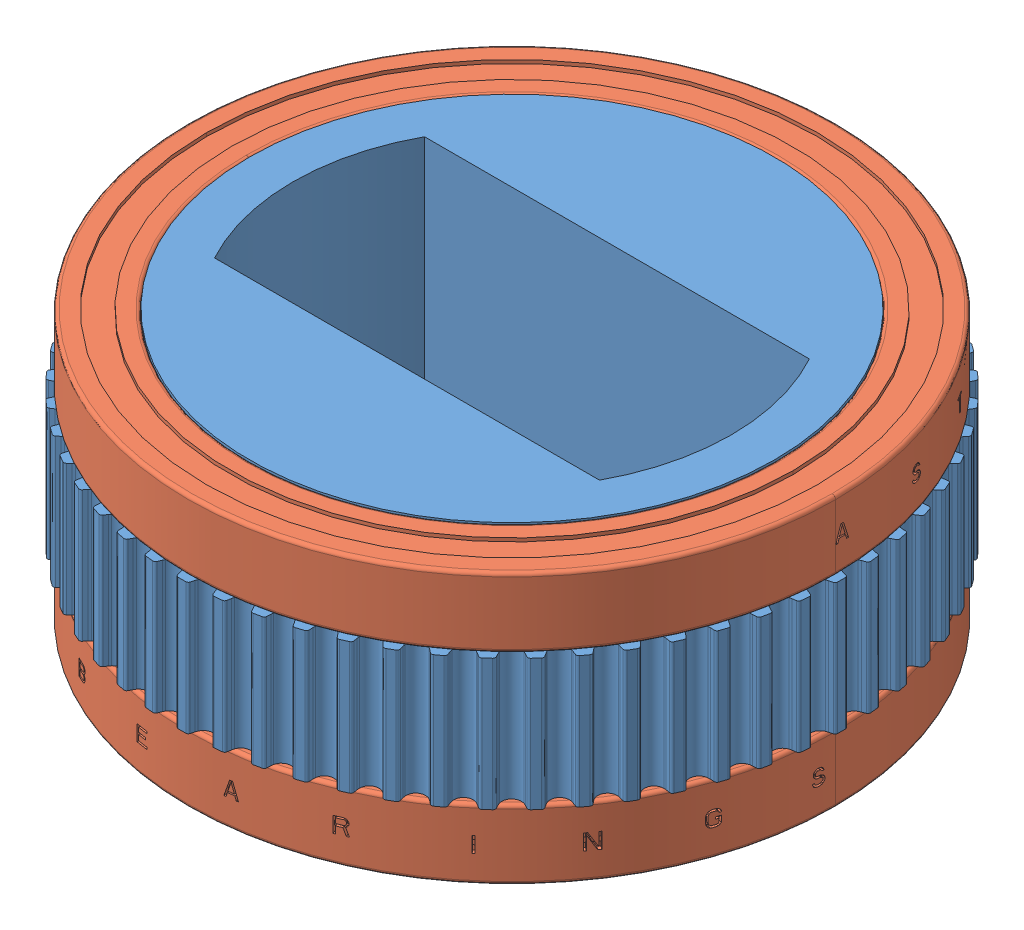
SolidWorks assembly Second_reduction_module, configuration Default. Lengths in mm.
Overall size (37.7 15.5 37.7).
5 component instances, 4 part files, 8 mates.
Components (placement in the parent):
- DRIVEN_PULLEY_SECOND_REDUCTION-1: DRIVEN_PULLEY_SECOND_REDUCTION [По умолчанию] at (8.5756 23.3079 32.9704) x (-1 0 0) z (0 -1 0) size (37.7 37.7 15.5)
- Bearings_6706-2RS.stp-1: Bearings_6706-2RS.stp [Default] at (8.5756 23.7518 32.9704) x (0 1 0) z (0 0 -1) size (3.99 37.01 37.01)
- Bearings_6706-2RS.stp-2: Bearings_6706-2RS.stp [Default] at (8.5756 12.264 32.9704) x (0 1 0) z (0 0 1) size (3.99 37.01 37.01)
- M3_INSERT.step-1: M3_INSERT.step [Default] at (8.5756 10.2579 42.9704) size (4.52 4 4.53)
- M3_INSERT.step-2: M3_INSERT.step [Default] at (8.5756 10.2579 22.9704) size (4.52 4 4.53)
Mates (geometry in assembly coordinates):
- Concentric1: concentric anti-aligned: cylinder of DRIVEN_PULLEY_SECOND_REDUCTION-1 through (8.5756 25.7579 32.9704) axis (0 -1 0) radius 15; cylinder of Bearings_6706-2RS.stp-1 through (8.5756 21.5585 32.9704) axis (0 1 0) radius 14.9987
- Coincident1: coincident anti-aligned: plane of DRIVEN_PULLEY_SECOND_REDUCTION-1 through (10.757 21.7579 14.3981) normal (0 1 0); plane of Bearings_6706-2RS.stp-1 through (8.5756 21.7579 32.9704) normal (0 -1 0)
- Coincident2: coincident anti-aligned: plane of DRIVEN_PULLEY_SECOND_REDUCTION-1 through (8.5756 14.2579 32.9704) normal (0 -1 0); plane of Bearings_6706-2RS.stp-2 through (8.5756 14.2579 32.9704) normal (0 1 0)
- Concentric2: concentric aligned: cylinder of DRIVEN_PULLEY_SECOND_REDUCTION-1 through (8.5756 10.2579 32.9704) axis (0 1 0) radius 15; cylinder of Bearings_6706-2RS.stp-2 through (8.5756 10.0707 32.9704) axis (0 1 0) radius 14.9987
- Concentric3: concentric aligned: cylinder of DRIVEN_PULLEY_SECOND_REDUCTION-1 through (8.5756 14.2579 22.9704) axis (0 -1 0) radius 2.25; cylinder of M3_INSERT.step-2 through (8.5756 10.2579 22.9704) axis (0 -1 0) radius 1.85
- Coincident3: coincident aligned: plane of DRIVEN_PULLEY_SECOND_REDUCTION-1 through (8.5756 10.2579 32.9704) normal (0 -1 0); plane of M3_INSERT.step-2 through (8.5756 10.2579 22.9704) normal (0 -1 0)
- Concentric4: concentric: cylinder of DRIVEN_PULLEY_SECOND_REDUCTION-1 through (8.5756 14.2579 42.9704) axis (0 -1 0) radius 2.25; cylinder of M3_INSERT.step-1 through (8.5756 10.2579 42.9704) axis (0 -1 0) radius 1.85
- Coincident4: coincident aligned: plane of DRIVEN_PULLEY_SECOND_REDUCTION-1 through (8.5756 10.2579 32.9704) normal (0 -1 0); plane of M3_INSERT.step-1 through (8.5756 10.2579 42.9704) normal (0 -1 0)
